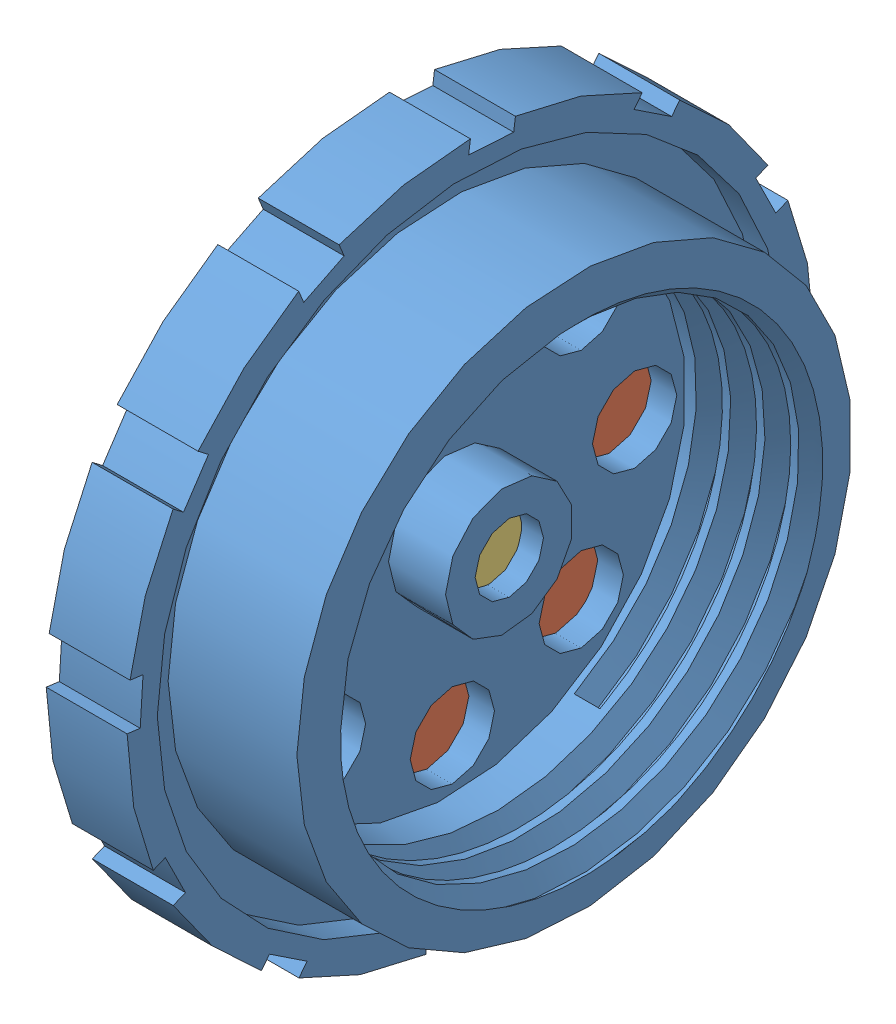
SolidWorks assembly Assy_Ambu-Bag_Inlet_Inner, configuration Default. Lengths in mm.
Overall size (17.91 60.3 60.3).
3 component instances, 3 part files, 4 mates.
Components (placement in the parent):
- Ambu-Bag_Inlet_Inner-1: Ambu-Bag_Inlet_Inner [Default] at origin size (17.56 60.3 60.3)
- Ambu-Bag_Inlet_Inner_Seal-1: Ambu-Bag_Inlet_Inner_Seal [Default] at (2.65 0 0) x (0 0 -1) z (1 0 0) size (51 51 0.6)
- Ambu-Bag_Inlet_Inner_Flange-1: Ambu-Bag_Inlet_Inner_Flange [Default] at (-0.35 0 0) size (9 26 26)
Mates (geometry in assembly coordinates):
- Coincident1: coincident: plane of Ambu-Bag_Inlet_Inner-1 through (3.25 0 0) normal (-1 0 0); plane of Ambu-Bag_Inlet_Inner_Seal-1 through (3.25 0 0) normal (1 0 0)
- Concentric1: concentric: cylinder of Ambu-Bag_Inlet_Inner-1 through (0 0 0) axis (1 0 0) radius 3; cylinder of Ambu-Bag_Inlet_Inner_Seal-1 through (3.25 0 0) axis (-1 0 0) radius 9.25
- Coincident2: coincident: plane of Ambu-Bag_Inlet_Inner-1 through (3.25 0 0) normal (-1 0 0); plane of Ambu-Bag_Inlet_Inner_Flange-1 through (3.25 9 0) normal (1 0 0)
- Concentric2: concentric: cylinder of Ambu-Bag_Inlet_Inner-1 through (0 0 0) axis (1 0 0) radius 3; cylinder of Ambu-Bag_Inlet_Inner_Flange-1 through (-0.35 0 0) axis (-1 0 0) radius 13
